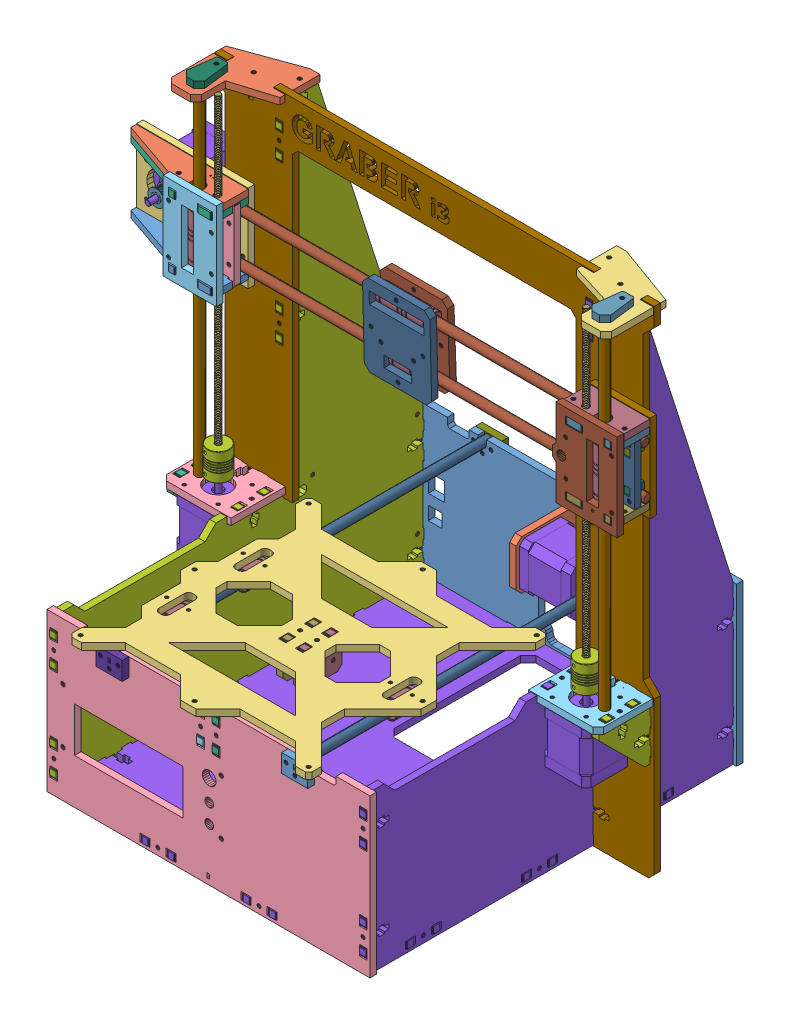
SolidWorks assembly Assem1, configuration Default. Lengths in mm.
Overall size (470.04 461.9 366.24).
68 component instances, 50 part files, 200 mates.
Components (placement in the parent):
- back part 1-1: back part 1 [Default] at (81.0271 401.4745 20.7029) x (-1 0 0) z (0 0 -1) size (296 144.5 6)
- back part 2-1: back part 2 [Default] at (199.6219 473.5631 193.2658) x (0 0 1) z (-1 0 0) size (71.85 45 6)
- bed-1: bed [Default] at (-163.14 330.8347 15.6908) x (1 0 0) z (0 -1 0) size (220.33 220.31 6)
- front part 1 screen-1: front part 1 screen [Default] at (294.9167 578.5677 350.6028) size (296 144.5 6)
- front part 2a-1: front part 2a [Default] at (183.3219 631.05 272.14) x (0 0 1) z (-1 0 0) size (40.75 45 6)
- front part 2b-1: front part 2b [Default] at (197.7219 678.4694 271.6813) x (0 0 1) z (-1 0 0) size (40.75 45 6)
- leg left-1: leg left [Default] at (48.822 231.9538 579.6805) x (0 0 1) z (-1 0 0) size (342.6 449.9 6)
- leg right-1: leg right [Default] at (326.8719 230.1655 151.8741) x (0 0 -1) z (1 0 0) size (342.6 449.9 6)
- main frame-1: main frame [Default] at (-176.0058 230.1655 143.6028) size (402.95 456 6)
- n1-1: n1 [Default] at (218.3242 369.7719 164.9112) x (1 0 0) z (0 -0.024034 0.999711) size (61.69 75.91 6)
- n2-1: n2 [Default] at (218.3242 294.4964 143.8985) x (1 0 0) z (0 -0.036374 0.999338) size (61.69 75.91 6)
- part p-1: part p [Default] at (183.563 14.2222 -89.1173) x (0 0 1) z (-1 0 0) size (38.6 31.35 6)
- part p b-1: part p b [Default] at (193.0605 14.3436 15.5535) x (0 1 0) z (1 0 0) size (31.35 38.6 6)
- small top a-1: small top a [Default] at (-87.2919 634.6064 375.2986) x (1 0 0) z (0 1 0) size (16.77 30.05 6)
- small top b-1: small top b [Default] at (-472.4014 634.6064 421.3951) x (1 0 0) z (0 1 0) size (16.77 30.05 6)
- smooth rod stop a-1: smooth rod stop a [Default] at (-150.0515 246.7717 8.7029) size (24 16.7 6)
- smooth rod stop b-1: smooth rod stop b [Default] at (-149.8049 227.3403 356.6028) size (24 16.7 6)
- smooth rod stop c-1: smooth rod stop c [Default] at (20.1883 207.2244 8.7029) size (24 16.7 6)
- smooth rod stop d-1: smooth rod stop d [Default] at (20.273 187.8996 356.6028) size (24 16.7 6)
- smooth rod top a-1: smooth rod top a [Default] at (-31.7202 634.6064 605.6389) x (0 0 -1) z (0 -1 0) size (75.26 65.68 6)
- smooth rod top b-1: smooth rod top b [Default] at (726.9539 628.6064 93.7708) x (-1 0 0) z (0 1 0) size (65.68 75.26 6)
- stepper base left-1: stepper base left [Default] at (-280.2567 316.9564 234.6953) x (1 0 0) z (0 1 0) size (64 56.35 6)
- stepper base right-1: stepper base right [Default] at (56.5293 316.9065 293.4958) x (1 0 0) z (0 1 0) size (64 56.35 6)
- stepper stand a-1: stepper stand a [Default] at (-9.948 -106.3457 57.6908) x (0 1 0) z (1 0 0) size (53.35 53.34 6)
- stepper stand b-1: stepper stand b [Default] at (385.6419 172.2943 -219.6051) x (0 0 1) z (-1 0 0) size (53.35 53.34 6)
- under bed-1: under bed [Default] at (-55.3058 181.7065 435.9358) x (0 0 1) z (0 1 0) size (342.6 289.5 6)
- x idler part 1-1: x idler part 1 [Default] at (847.1674 642.4594 153.83) size (59 79.9 6)
- x idler part 2-1: x idler part 2 [Default] at (787.0156 643.2594 167.8319) size (59 65.1 6)
- x idler part 3-1: x idler part 3 [Default] at (727.0679 642.4594 184.03) size (59 79.9 6)
- x idler part 4-1: x idler part 4 [Default] at (484.4835 487.9462 483.2321) x (0 0 1) z (0 1 0) size (36.8 55 6)
- x idler part 5-1: x idler part 5 [Default] at (847.3015 547.8462 -9.8219) x (1 0 0) z (0 1 0) size (55 23.6 6)
- x idler part 6-1: x idler part 6 [Default] at (790.9011 547.8462 -9.4918) x (1 0 0) z (0 1 0) size (55 36.8 6)
- x idler part 7a-1: x idler part 7a [Default] at (755.5095 496.5462 -13.5225) x (1 0 0) z (0 1 0) size (29.97 17.5 6)
- x idler part 7b-1: x idler part 7b [Default] at (724.0344 527.1462 -13.5044) x (1 0 0) z (0 1 0) size (29.97 17.5 6)
- x motor part 1-1: x motor part 1 [Default] at (491.673 525.4551 -71.4672) x (1 0 0) z (0 1 0) size (29.97 17.5 6)
- x motor part 1b-1: x motor part 1b [Default] at (449.1595 495.6551 -77.763) x (1 0 0) z (0 1 0) size (29.97 17.5 6)
- x motor part 2-1: x motor part 2 [Default] at (-481.484 487.0551 437.8787) x (-1 0 0) z (0 1 0) size (102.7 36.8 6)
- x motor part 3-1: x motor part 3 [Default] at (-377.0341 546.9551 445.1095) x (-1 0 0) z (0 1 0) size (102.7 23.6 6)
- x motor part 4-1: x motor part 4 [Default] at (434.2486 839.5242 154.4392) size (102.3 79.9 6)
- x motor part 5-1: x motor part 5 [Default] at (384.0037 188.4825 174.4392) x (1 0 0) z (0 0 -1) size (48.7 65.1 6)
- x motor part 6-1: x motor part 6 [Default] at (332.3799 840.721 184.0392) size (48.7 79.9 6)
- x motor part 7-1: x motor part 7 [Default] at (434.9095 546.9551 -213.9017) x (1 0 0) z (0 1 0) size (102.7 36.8 6)
- Flexi_spojka_5x5-1: Flexi_spojka_5x5 [Default] at (19.3155 338.4564 178.8274) x (0 1 0) z (0 0 1) size (25 21.03 20)
- nema17-1: nema17 [Défaut] at (356.4592 316.9065 178.8223) x (1 0 0.000118) z (0 -1 0) size (42 42 71)
- smooth rod 8x317-1: smooth rod 8x317 [Default] at (2.2936 316.9564 178.9402) size (8 317 8)
- smooth rod 8x342-1: smooth rod 8x342 [Default] at (272.9623 319.2422 14.6028) x (-0.956375 -0.292142 0) z (-0.292142 0.956375 0) size (8 342 8)
- smooth rod 8x400-1: smooth rod 8x400 [Default] at (-4.2443 491.9462 162.4699) x (0 -1 0) z (0 0 1) size (8 400 8)
- smooth rod 8x342-2: smooth rod 8x342 [Default] at (102.9608 319.2481 14.6028) x (-0.222657 0.974897 0) z (0.974897 0.222657 0) size (8 342 8)
- nema17-2: nema17 [Défaut] at (19.3155 316.9564 178.8274) x (1 0 0) z (0 -1 0) size (42 42 71)
- threaded rod 5mm-1: threaded rod 5mm [Défaut] at (356.4592 632.9065 178.8223) x (0 -1 0) z (0 0 1) size (293.85 5.77 5.1)
- threaded rod 5mm-2: threaded rod 5mm [Défaut] at (19.3155 632.9564 178.8274) x (0 -1 0) z (-0.747424 0 0.664347) size (293.85 5.77 5.1)
- Flexi_spojka_5x5-2: Flexi_spojka_5x5 [Default] at (356.4592 338.4065 178.8223) x (0 1 0) z (0.084195 0 0.996449) size (25 21.03 20)
- smooth rod 8x317-2: smooth rod 8x317 [Default] at (373.3732 316.9065 178.9309) size (8 317 8)
- LM8UU-1: LM8UU [Default] at (102.9608 319.2481 230.7856) x (0 0 -1) z (0.945065 -0.326884 0) size (24 15 15)
- LM8UU-2: LM8UU [Default] at (102.9608 319.2481 300.7926) x (0 0 1) z (-0.81584 -0.578277 0) size (24 15 15)
- LM8UU-3: LM8UU [Default] at (272.9623 319.2422 264.6485) x (0 0 1) z (-0.995879 -0.090696 0) size (24 15 15)
- LM8UU-4: LM8UU [Default] at (2.2936 527.4051 178.9402) x (0 1 0) z (-0.980384 0 0.197099) size (24 15 15)
- smooth rod 8x400-2: smooth rod 8x400 [Default] at (-4.2443 536.9551 163.83) x (0 -1 0) z (0 0 1) size (8 400 8)
- LM8UU-5: LM8UU [Default] at (2.2936 503.4051 178.9402) x (0 1 0) z (-0.980384 0 0.197099) size (24 15 15)
- LM8UU-6: LM8UU [Default] at (191.6084 536.9551 163.83) x (1 0 0) z (0 0.980384 0.197099) size (24 15 15)
- LM8UU-7: LM8UU [Default] at (178.1084 491.9462 162.4699) x (-1 0 0) z (0 -0.980384 0.197099) size (24 15 15)
- LM8UU-8: LM8UU [Default] at (167.6084 536.9551 163.83) x (-1 0 0) z (0 -0.980384 0.197099) size (24 15 15)
- LM8UU-9: LM8UU [Default] at (373.3732 503.4962 178.9309) x (0 -1 0) z (-0.81584 0 -0.578277) size (24 15 15)
- LM8UU-10: LM8UU [Default] at (373.3732 527.4962 178.9309) x (0 1 0) z (-0.81584 0 0.578277) size (24 15 15)
- nema17-3: nema17 [Défaut] at (-46.089 513.5551 154.4392) x (1 0 0) z (0 0 -1) size (42 42 71)
- nema17-4: nema17 [Défaut] at (199.6219 299.8274 62.2029) x (0 -1 0) z (1 0 0) size (42 42 71)
- GT2_20tooth-1: GT2_20tooth [Конфигурация1] at (197.8286 299.8274 62.2029) x (-1 0 0) z (0 -0.924225 -0.381849) size (14 15 15)
- GT2_20tooth-2: GT2_20tooth [Конфигурация1] at (-46.089 513.5551 156.4392) x (0 0 1) z (-1 0 0) size (14 15 15)
Mates (geometry in assembly coordinates):
- Distance1: distance = 0.35 mm anti-aligned: plane of leg left-1 through (42.822 231.9538 579.6805) normal (-1 0 0); plane of main frame-1 through (42.472 230.1655 149.6028) normal (1 0 0)
- Coincident2: coincident anti-aligned: plane of leg left-1 through (42.822 231.9538 143.6028) normal (0 0 1); plane of main frame-1 through (-176.0058 230.1655 143.6028) normal (0 0 -1)
- Coincident4: coincident aligned: plane of leg left-1 through (42.822 178.7065 579.6805) normal (0 -1 0); plane of main frame-1 through (-176.0058 178.7065 149.6028) normal (0 -1 0)
- Coincident5: coincident anti-aligned: plane of leg right-1 through (332.8719 230.1655 143.6028) normal (0 0 1); plane of main frame-1 through (-176.0058 230.1655 143.6028) normal (0 0 -1)
- Coincident6: coincident aligned: plane of leg left-1 through (42.822 178.7065 579.6805) normal (0 -1 0); plane of leg right-1 through (332.8719 178.7065 151.8741) normal (0 -1 0)
- Distance2: distance = 0.35 mm anti-aligned: plane of leg right-1 through (332.8719 230.1655 151.8741) normal (1 0 0); plane of main frame-1 through (333.2219 230.1655 149.6028) normal (-1 0 0)
- Coincident8: coincident anti-aligned: plane of front part 1 screen-1 through (294.9167 578.5677 350.6028) normal (0 0 -1); plane of leg left-1 through (42.822 231.9538 350.6028) normal (0 0 1)
- Coincident9: coincident aligned: plane of front part 1 screen-1 through (294.9167 178.7065 356.6028) normal (0 -1 0); plane of leg left-1 through (42.822 178.7065 579.6805) normal (0 -1 0)
- Coincident11: coincident anti-aligned: plane of front part 1 screen-1 through (42.822 578.5677 356.6028) normal (1 0 0); plane of leg left-1 through (42.822 231.9538 579.6805) normal (-1 0 0)
- Coincident12: coincident anti-aligned: plane of back part 1-1 through (81.0271 401.4745 20.7029) normal (0 0 1); plane of leg right-1 through (332.8719 230.1655 20.7029) normal (0 0 -1)
- Coincident13: coincident aligned: plane of back part 1-1 through (81.0271 178.7065 14.7029) normal (0 -1 0); plane of leg right-1 through (332.8719 178.7065 151.8741) normal (0 -1 0)
- Coincident15: coincident aligned: plane of back part 1-1 through (335.9719 401.4745 14.7029) normal (1 0 0); plane of front part 1 screen-1 through (335.9719 578.5677 356.6028) normal (1 0 0)
- Parallel2: parallel anti-aligned: plane of leg right-1 through (332.8719 178.7065 151.8741) normal (0 -1 0); plane of under bed-1 through (-55.3058 187.7065 435.9358) normal (0 1 0)
- Coincident17: coincident anti-aligned: plane of back part 1-1 through (81.0271 401.4745 20.7029) normal (0 0 1); plane of under bed-1 through (-55.3058 187.7065 20.7029) normal (0 0 -1)
- Coincident18: coincident anti-aligned: plane of leg left-1 through (42.822 181.7065 579.6805) normal (0 1 0); plane of under bed-1 through (-55.3058 181.7065 435.9358) normal (0 -1 0)
- Coincident19: coincident anti-aligned: plane of leg right-1 through (326.8719 230.1655 151.8741) normal (-1 0 0); plane of under bed-1 through (326.8719 187.7065 435.9358) normal (1 0 0)
- Coincident20: coincident anti-aligned: plane of main frame-1 through (-176.0058 230.1655 149.6028) normal (0 0 1); plane of stepper base left-1 through (-280.2567 322.9564 149.6028) normal (0 0 -1)
- Coincident22: coincident anti-aligned: plane of main frame-1 through (-176.0058 316.9564 149.6028) normal (0 1 0); plane of stepper base left-1 through (-280.2567 316.9564 234.6953) normal (0 -1 0)
- Coincident23: coincident anti-aligned: plane of stepper base left-1 through (-280.2567 316.9564 234.6953) normal (0 -1 0); plane of stepper stand a-1 through (-3.948 316.9564 57.6908) normal (0 1 0)
- Coincident24: coincident anti-aligned: plane of main frame-1 through (-176.0058 230.1655 149.6028) normal (0 0 1); plane of stepper stand a-1 through (-3.948 -106.3457 149.6028) normal (0 0 -1)
- Coincident25: coincident anti-aligned: plane of stepper base left-1 through (-3.948 322.9564 234.6953) normal (-1 0 0); plane of stepper stand a-1 through (-3.948 -106.3457 57.6908) normal (1 0 0)
- Distance4: distance = 0.33 mm anti-aligned: plane of leg left-1 through (42.822 231.9538 579.6805) normal (-1 0 0); plane of stepper base left-1 through (42.492 322.9564 234.6953) normal (1 0 0)
- Coincident27: coincident anti-aligned: plane of main frame-1 through (-176.0058 230.1655 149.6028) normal (0 0 1); plane of stepper base right-1 through (56.5293 322.9065 149.6028) normal (0 0 -1)
- Coincident28: coincident anti-aligned: plane of leg right-1 through (332.8719 316.9065 151.8741) normal (0 1 0); plane of stepper base right-1 through (56.5293 316.9065 293.4958) normal (0 -1 0)
- Distance5: distance = 0.33 mm anti-aligned: plane of leg right-1 through (332.8719 230.1655 151.8741) normal (1 0 0); plane of stepper base right-1 through (333.2019 322.9065 293.4958) normal (-1 0 0)
- Coincident30: coincident anti-aligned: plane of stepper base right-1 through (56.5293 316.9065 293.4958) normal (0 -1 0); plane of stepper stand b-1 through (379.6419 316.9065 -219.6051) normal (0 1 0)
- Coincident31: coincident anti-aligned: plane of main frame-1 through (-176.0058 230.1655 149.6028) normal (0 0 1); plane of stepper stand b-1 through (379.6419 172.2943 149.6028) normal (0 0 -1)
- Coincident32: coincident anti-aligned: plane of stepper base right-1 through (379.6419 322.9065 293.4958) normal (1 0 0); plane of stepper stand b-1 through (379.6419 172.2943 -219.6051) normal (-1 0 0)
- Tangent1: tangent anti-aligned: plane of front part 1 screen-1 through (260.4614 316.8535 356.6028) normal (0.130526 0.991445 0); cylinder of smooth rod 8x342-1 through (272.9623 319.2422 356.6028) axis (0 0 -1) radius 4
- Tangent2: tangent anti-aligned: plane of front part 1 screen-1 through (414.4603 422.7756 356.6028) normal (-0.608761 0.793353 0); cylinder of smooth rod 8x342-1 through (272.9623 319.2422 356.6028) axis (0 0 -1) radius 4
- Tangent3: tangent anti-aligned: plane of front part 1 screen-1 through (173.5914 285.6624 356.6028) normal (0.382683 0.92388 0); cylinder of smooth rod 8x342-2 through (102.9608 319.2481 356.6028) axis (0 0 -1) radius 4
- Tangent4: tangent anti-aligned: plane of front part 1 screen-1 through (302.513 572.7389 356.6028) normal (-0.793353 0.608761 0); cylinder of smooth rod 8x342-2 through (102.9608 319.2481 356.6028) axis (0 0 -1) radius 4
- Coincident34: coincident anti-aligned: plane of back part 1-1 through (81.0271 401.4745 14.7029) normal (0 0 -1); plane of smooth rod stop a-1 through (-150.0515 246.7717 14.7029) normal (0 0 1)
- Coincident35: coincident anti-aligned: plane of front part 1 screen-1 through (294.9167 578.5677 356.6028) normal (0 0 1); plane of smooth rod stop d-1 through (20.273 187.8996 356.6028) normal (0 0 -1)
- Coincident36: coincident anti-aligned: plane of front part 1 screen-1 through (294.9167 578.5677 356.6028) normal (0 0 1); plane of smooth rod stop b-1 through (-149.8049 227.3403 356.6028) normal (0 0 -1)
- Coincident37: coincident anti-aligned: plane of back part 1-1 through (81.0271 401.4745 14.7029) normal (0 0 -1); plane of smooth rod stop c-1 through (20.1883 207.2244 14.7029) normal (0 0 1)
- Coincident38: coincident anti-aligned: plane of smooth rod stop b-1 through (-149.8049 227.3403 356.6028) normal (0 0 -1); plane of smooth rod 8x342-2 through (102.9608 319.2481 356.6028) normal (0 0 1)
- Coincident39: coincident aligned: plane of front part 1 screen-1 through (294.9167 323.2065 356.6028) normal (0 1 0); plane of smooth rod stop b-1 through (-149.8049 323.2065 362.6028) normal (0 1 0)
- Coincident40: coincident anti-aligned: plane of smooth rod stop d-1 through (20.273 187.8996 356.6028) normal (0 0 -1); plane of smooth rod 8x342-1 through (272.9623 319.2422 356.6028) normal (0 0 1)
- Coincident41: coincident aligned: plane of front part 1 screen-1 through (294.9167 323.2065 356.6028) normal (0 1 0); plane of smooth rod stop d-1 through (20.273 323.2065 362.6028) normal (0 1 0)
- Coincident42: coincident aligned: plane of back part 1-1 through (81.0271 323.2065 14.7029) normal (0 1 0); plane of smooth rod stop a-1 through (-150.0515 323.2065 14.7029) normal (0 1 0)
- Coincident43: coincident aligned: plane of back part 1-1 through (81.0271 323.2065 14.7029) normal (0 1 0); plane of smooth rod stop c-1 through (20.1883 323.2065 14.7029) normal (0 1 0)
- Coincident44: coincident aligned: plane of front part 1 screen-1 through (257.4547 294.0152 356.6028) normal (0.130526 0.991445 0); plane of smooth rod stop b-1 through (-134.2381 345.5825 362.6028) normal (0.130526 0.991445 0)
- Coincident45: coincident aligned: plane of front part 1 screen-1 through (260.6236 318.0852 356.6028) normal (0.130526 0.991445 0); plane of smooth rod stop d-1 through (41.2152 346.9709 362.6028) normal (0.130526 0.991445 0)
- Coincident46: coincident aligned: plane of back part 1-1 through (96.2765 285.6441 14.7029) normal (-0.130526 0.991445 0); plane of smooth rod stop c-1 through (11.3363 274.4615 14.7029) normal (-0.130526 0.991445 0)
- Coincident47: coincident aligned: plane of back part 1-1 through (93.3802 307.6437 14.7029) normal (-0.130526 0.991445 0); plane of smooth rod stop a-1 through (-153.7816 275.1042 14.7029) normal (-0.130526 0.991445 0)
- Coincident48: coincident anti-aligned: plane of stepper base right-1 through (56.5293 316.9065 293.4958) normal (0 -1 0); plane of nema17-1 through (356.4592 316.9065 178.8223) normal (0 1 0)
- Tangent5: tangent anti-aligned: plane of stepper base right-1 through (138.3592 322.9065 95.941) normal (-0.382683 0 0.92388); cylinder of nema17-1 through (371.9574 311.9065 194.3241) axis (0 1 0) radius 1.5
- Tangent6: tangent anti-aligned: plane of stepper base right-1 through (74.4052 322.9065 157.7152) normal (-0.130526 0 0.991445); cylinder of nema17-1 through (340.9574 311.9065 194.3204) axis (0 1 0) radius 1.5
- Tangent7: tangent anti-aligned: plane of stepper base right-1 through (237.2066 322.9065 58.0326) normal (-0.608761 0 0.793353); cylinder of nema17-1 through (371.9611 311.9065 163.3241) axis (0 1 0) radius 1.5
- Coincident49: coincident anti-aligned: plane of stepper base left-1 through (-280.2567 316.9564 234.6953) normal (0 -1 0); plane of nema17-2 through (19.3155 316.9564 178.8274) normal (0 1 0)
- Tangent8: tangent anti-aligned: plane of stepper base left-1 through (-219.2692 322.9564 87.4585) normal (-0.382683 0 0.92388); cylinder of nema17-2 through (34.8155 311.9564 194.3274) axis (0 1 0) radius 1.5
- Tangent9: tangent anti-aligned: plane of stepper base left-1 through (-154.5729 322.9564 70.901) normal (-0.608761 0 0.793353); cylinder of nema17-2 through (3.8155 311.9564 194.3274) axis (0 1 0) radius 1.5
- Tangent10: tangent anti-aligned: plane of stepper base left-1 through (-212.8489 322.9564 71.9585) normal (-0.382683 0 0.92388); cylinder of nema17-2 through (3.8155 311.9564 163.3274) axis (0 1 0) radius 1.5
- Concentric1: concentric anti-aligned: cylinder of nema17-1 through (356.4592 340.9065 178.8223) axis (0 -1 0) radius 2.5; cylinder of threaded rod 5mm-1 through (356.4592 340.9065 178.8223) axis (0 1 0) radius 2.5
- Coincident50: coincident anti-aligned: plane of nema17-1 through (356.4592 340.9065 178.8223) normal (0 1 0); plane of threaded rod 5mm-1 through (356.4592 340.9065 178.8223) normal (0 -1 0)
- Concentric2: concentric anti-aligned: cylinder of nema17-2 through (19.3155 340.9564 178.8274) axis (0 -1 0) radius 2.5; cylinder of threaded rod 5mm-2 through (19.3155 340.9564 178.8274) axis (0 1 0) radius 2.5
- Coincident51: coincident anti-aligned: plane of nema17-2 through (19.3155 340.9564 178.8274) normal (0 1 0); plane of threaded rod 5mm-2 through (19.3155 340.9564 178.8274) normal (0 -1 0)
- Concentric3: concentric anti-aligned: cylinder of nema17-1 through (356.4592 340.9065 178.8223) axis (0 -1 0) radius 2.5; cylinder of Flexi_spojka_5x5-2 through (356.4592 330.9065 178.8223) axis (0 1 0) radius 2.5
- Concentric4: concentric anti-aligned: cylinder of Flexi_spojka_5x5-1 through (19.3155 330.9564 178.8274) axis (0 1 0) radius 2.5; cylinder of nema17-2 through (19.3155 340.9564 178.8274) axis (0 -1 0) radius 2.5
- Distance6: distance = 12 mm anti-aligned: plane of Flexi_spojka_5x5-1 through (19.3155 330.9564 178.8274) normal (0 -1 0); plane of nema17-2 through (19.3155 318.9564 178.8274) normal (0 1 0)
- Distance7: distance = 12 mm anti-aligned: plane of Flexi_spojka_5x5-2 through (356.4592 330.9065 178.8223) normal (0 -1 0); plane of nema17-1 through (356.4592 318.9065 178.8223) normal (0 1 0)
- Coincident54: coincident anti-aligned: plane of main frame-1 through (-176.0058 628.6064 149.6028) normal (0 1 0); plane of smooth rod top a-1 through (-31.7202 628.6064 605.6389) normal (0 -1 0)
- Coincident55: coincident anti-aligned: plane of main frame-1 through (-176.0058 230.1655 143.6028) normal (0 0 -1); plane of smooth rod top a-1 through (-31.7202 628.6064 143.6028) normal (0 0 1)
- Coincident57: coincident anti-aligned: plane of main frame-1 through (-176.0058 628.6064 149.6028) normal (0 1 0); plane of smooth rod top b-1 through (726.9539 628.6064 93.7708) normal (0 -1 0)
- Coincident58: coincident anti-aligned: plane of main frame-1 through (-176.0058 230.1655 143.6028) normal (0 0 -1); plane of smooth rod top b-1 through (726.9539 634.6064 143.6028) normal (0 0 1)
- Tangent11: tangent anti-aligned: plane of stepper base right-1 through (77.2753 322.9065 135.9144) normal (-0.130526 0 0.991445); cylinder of smooth rod 8x317-2 through (373.3732 633.9065 178.9309) axis (0 -1 0) radius 4
- Tangent12: tangent anti-aligned: plane of stepper base right-1 through (290.1632 322.9065 390.2701) normal (-0.92388 0 -0.382683); cylinder of smooth rod 8x317-2 through (373.3732 633.9065 178.9309) axis (0 -1 0) radius 4
- Coincident60: coincident aligned: plane of stepper base right-1 through (56.5293 316.9065 293.4958) normal (0 -1 0); plane of smooth rod 8x317-2 through (373.3732 316.9065 178.9309) normal (0 -1 0)
- Coincident61: coincident anti-aligned: plane of main frame-1 through (334.7219 230.1655 149.6028) normal (1 0 0); plane of smooth rod top b-1 through (334.7219 634.6064 93.7708) normal (-1 0 0)
- Tangent14: tangent anti-aligned: plane of stepper base left-1 through (-267.7055 322.9564 139.3596) normal (-0.130526 0 0.991445); cylinder of smooth rod 8x317-1 through (2.2936 633.9564 178.9402) axis (0 -1 0) radius 4
- Tangent15: tangent anti-aligned: plane of stepper base left-1 through (-62.4929 322.9564 324.896) normal (0.92388 0 0.382683); cylinder of smooth rod 8x317-1 through (2.2936 633.9564 178.9402) axis (0 -1 0) radius 4
- Coincident62: coincident aligned: plane of stepper base left-1 through (-280.2567 316.9564 234.6953) normal (0 -1 0); plane of smooth rod 8x317-1 through (2.2936 316.9564 178.9402) normal (0 -1 0)
- Coincident63: coincident anti-aligned: plane of main frame-1 through (40.972 230.1655 149.6028) normal (-1 0 0); plane of smooth rod top a-1 through (40.972 628.6064 605.6389) normal (1 0 0)
- Concentric5: concentric anti-aligned: cylinder of smooth rod 8x342-2 through (102.9608 319.2481 356.6028) axis (0 0 -1) radius 4; cylinder of LM8UU-1 through (102.9608 319.2481 276.4751) axis (0 0 1) radius 4
- Concentric61: concentric aligned: cylinder of smooth rod 8x342-2 through (102.9608 319.2481 356.6028) axis (0 0 -1) radius 4; cylinder of LM8UU-2 through (102.9608 319.2481 255.1031) axis (0 0 -1) radius 7.5
- Concentric71: concentric aligned: cylinder of smooth rod 8x342-1 through (272.9623 319.2422 356.6028) axis (0 0 -1) radius 4; cylinder of LM8UU-3 through (272.9623 319.2422 218.959) axis (0 0 -1) radius 7.5
- Coincident64: coincident anti-aligned: plane of back part 1-1 through (81.0271 401.4745 20.7029) normal (0 0 1); plane of back part 2-1 through (193.6219 473.5631 20.7029) normal (0 0 -1)
- Coincident65: coincident anti-aligned: plane of back part 1-1 through (193.6219 401.4745 14.7029) normal (1 0 0); plane of back part 2-1 through (193.6219 473.5631 193.2658) normal (-1 0 0)
- Coincident66: coincident anti-aligned: plane of back part 1-1 through (81.0271 307.4274 14.7029) normal (0 1 0); plane of back part 2-1 through (193.6219 307.4274 193.2658) normal (0 -1 0)
- Coincident67: coincident aligned: plane of front part 2a-1 through (177.3219 631.05 350.6028) normal (0 0 1); plane of front part 2b-1 through (191.7219 678.4694 350.6028) normal (0 0 1)
- Coincident68: coincident anti-aligned: plane of front part 1 screen-1 through (294.9167 578.5677 350.6028) normal (0 0 -1); plane of front part 2b-1 through (191.7219 678.4694 350.6028) normal (0 0 1)
- Coincident69: coincident anti-aligned: plane of front part 1 screen-1 through (294.9167 317.2465 356.6028) normal (0 -1 0); plane of front part 2a-1 through (177.3219 317.2465 272.14) normal (0 1 0)
- Coincident71: coincident anti-aligned: plane of front part 1 screen-1 through (191.7219 578.5677 356.6028) normal (1 0 0); plane of front part 2b-1 through (191.7219 678.4694 271.6813) normal (-1 0 0)
- Coincident72: coincident anti-aligned: plane of front part 1 screen-1 through (177.3219 578.5677 356.6028) normal (1 0 0); plane of front part 2a-1 through (177.3219 631.05 272.14) normal (-1 0 0)
- Coincident73: coincident anti-aligned: plane of front part 1 screen-1 through (294.9167 308.0465 356.6028) normal (0 1 0); plane of front part 2b-1 through (191.7219 308.0465 271.6813) normal (0 -1 0)
- Coincident74: coincident anti-aligned: plane of small top b-1 through (-472.4014 634.6064 421.3951) normal (0 -1 0); plane of smooth rod top a-1 through (-31.7202 634.6064 605.6389) normal (0 1 0)
- Coincident75: coincident anti-aligned: plane of small top a-1 through (-87.2919 634.6064 375.2986) normal (0 -1 0); plane of smooth rod top b-1 through (726.9539 634.6064 93.7708) normal (0 1 0)
- Coincident76: coincident aligned: plane of small top a-1 through (-52.2335 640.6064 109.0039) normal (0.130526 0 -0.991445); plane of smooth rod top b-1 through (711.7076 634.6064 209.5786) normal (0.130526 0 -0.991445)
- Coincident77: coincident aligned: plane of small top a-1 through (-17.731 640.6064 465.9521) normal (-0.608761 0 -0.793353); plane of smooth rod top b-1 through (630.7306 634.6064 -31.63) normal (-0.608761 0 -0.793353)
- Coincident78: coincident aligned: plane of small top b-1 through (25.4669 640.6064 355.8495) normal (0.991445 0 -0.130526); plane of smooth rod top a-1 through (56.8178 628.6064 593.9827) normal (0.991445 0 -0.130526)
- Coincident79: coincident aligned: plane of small top b-1 through (-312.3674 640.6064 35.039) normal (0.382683 0 -0.92388); plane of smooth rod top a-1 through (128.9175 628.6064 217.8252) normal (0.382683 0 -0.92388)
- Parallel3: parallel anti-aligned: plane of bed-1 through (-163.14 324.8347 15.6908) normal (0 -1 0); plane of leg left-1 through (42.822 313.2065 579.6805) normal (0 1 0)
- Coincident80: coincident: line of bed-1 through (107.9649 324.8347 241.7856) axis (0 0 -1); cylinder of LM8UU-1 through (102.9608 319.2481 276.4751) axis (0 0 1) radius 7.5
- Coincident81: coincident: line of bed-1 through (107.9649 324.8347 311.7926) axis (0 0 -1); cylinder of LM8UU-2 through (102.9608 319.2481 255.1031) axis (0 0 -1) radius 7.5
- Coincident82: coincident: line of bed-1 through (267.9648 324.8347 252.6485) axis (0 0 1); cylinder of LM8UU-3 through (272.9623 319.2422 218.959) axis (0 0 -1) radius 7.5
- Distance8: distance = 4 mm anti-aligned: plane of bed-1 through (-163.14 324.8347 284.7926) normal (0 0 1); plane of LM8UU-2 through (102.9608 319.2481 288.7926) normal (0 0 -1)
- Distance9: distance = 4 mm anti-aligned: plane of LM8UU-1 through (102.9608 319.2481 218.7856) normal (0 0 -1); plane of bed-1 through (-163.14 324.8347 214.7856) normal (0 0 1)
- Distance10: distance = 4 mm anti-aligned: plane of LM8UU-3 through (272.9623 319.2422 252.6485) normal (0 0 -1); plane of bed-1 through (-163.14 324.8347 248.6485) normal (0 0 1)
- Coincident86: coincident anti-aligned: plane of x motor part 3-1 through (-377.0341 552.9551 160.4392) normal (0 0 -1); plane of x motor part 4-1 through (434.2486 839.5242 160.4392) normal (0 0 1)
- Coincident87: coincident anti-aligned: plane of x motor part 2-1 through (-481.484 481.0551 160.4392) normal (0 0 -1); plane of x motor part 4-1 through (434.2486 839.5242 160.4392) normal (0 0 1)
- Coincident88: coincident anti-aligned: plane of x motor part 4-1 through (434.2486 839.5242 160.4392) normal (0 0 1); plane of x motor part 7-1 through (434.9095 540.9551 160.4392) normal (0 0 -1)
- Parallel4: parallel aligned: plane of x motor part 4-1 through (-74.089 839.5242 160.4392) normal (-1 0 0); plane of x motor part 7-1 through (-74.289 540.9551 -213.9017) normal (-1 0 0)
- Parallel5: parallel aligned: plane of x motor part 3-1 through (-74.289 552.9551 445.1095) normal (-1 0 0); plane of x motor part 4-1 through (-74.089 839.5242 160.4392) normal (-1 0 0)
- Parallel6: parallel aligned: plane of x motor part 2-1 through (-74.289 481.0551 437.8787) normal (-1 0 0); plane of x motor part 4-1 through (-74.089 839.5242 160.4392) normal (-1 0 0)
- Coincident89: coincident anti-aligned: plane of x motor part 2-1 through (23.211 481.0551 437.8787) normal (1 0 0); plane of x motor part 4-1 through (23.211 839.5242 160.4392) normal (-1 0 0)
- Coincident90: coincident anti-aligned: plane of x motor part 4-1 through (23.211 839.5242 160.4392) normal (-1 0 0); plane of x motor part 7-1 through (23.211 540.9551 -213.9017) normal (1 0 0)
- Coincident91: coincident anti-aligned: plane of x motor part 2-1 through (-481.484 487.0551 437.8787) normal (0 1 0); plane of x motor part 4-1 through (434.2486 487.0551 160.4392) normal (0 -1 0)
- Coincident92: coincident anti-aligned: plane of x motor part 4-1 through (434.2486 546.9551 160.4392) normal (0 -1 0); plane of x motor part 7-1 through (434.9095 546.9551 -213.9017) normal (0 1 0)
- Coincident93: coincident anti-aligned: plane of x motor part 3-1 through (-377.0341 546.9551 445.1095) normal (0 -1 0); plane of x motor part 7-1 through (434.9095 546.9551 -213.9017) normal (0 1 0)
- Coincident94: coincident aligned: plane of x motor part 3-1 through (28.4093 552.9551 445.1095) normal (1 0 0); plane of x motor part 7-1 through (28.4093 540.9551 -213.9017) normal (1 0 0)
- Coincident95: coincident anti-aligned: plane of x motor part 6-1 through (332.3799 840.721 184.0392) normal (0 0 -1); plane of x motor part 7-1 through (434.9095 540.9551 184.0392) normal (0 0 1)
- Coincident96: coincident anti-aligned: plane of x motor part 6-1 through (332.3799 540.9551 190.0392) normal (0 1 0); plane of x motor part 7-1 through (434.9095 540.9551 -213.9017) normal (0 -1 0)
- Coincident97: coincident anti-aligned: plane of x motor part 2-1 through (11.5987 481.0551 437.8787) normal (-1 0 0); plane of x motor part 6-1 through (11.5987 840.721 190.0392) normal (1 0 0)
- Tangent19: tangent: line of x motor part 6-1 through (7.7935 489.4051 184.0392) axis (0 1 0); cylinder of LM8UU-4 through (2.2936 481.7156 178.9402) axis (0 -1 0) radius 7.5
- Tangent17: tangent: line of x motor part 6-1 through (-3.2064 539.4051 184.0392) axis (0 -1 0); cylinder of LM8UU-4 through (2.2936 481.7156 178.9402) axis (0 -1 0) radius 7.5
- Concentric8: concentric aligned: cylinder of LM8UU-4 through (2.2936 481.7156 178.9402) axis (0 -1 0) radius 7.5; cylinder of LM8UU-5 through (2.2936 457.7156 178.9402) axis (0 -1 0) radius 7.5
- Coincident101: coincident anti-aligned: plane of LM8UU-4 through (2.2936 515.4051 178.9402) normal (0 -1 0); plane of LM8UU-5 through (2.2936 515.4051 178.9402) normal (0 1 0)
- Coincident102: coincident anti-aligned: plane of x motor part 6-1 through (332.3799 539.4051 190.0392) normal (0 -1 0); plane of LM8UU-4 through (2.2936 539.4051 178.9402) normal (0 1 0)
- Parallel7: parallel anti-aligned: plane of x motor part 4-1 through (434.2486 839.5242 160.4392) normal (0 0 1); plane of x motor part 5-1 through (384.0037 188.4825 168.4392) normal (0 0 -1)
- Tangent20: tangent: line of x motor part 5-1 through (8.2928 526.2551 174.4392) axis (0 -1 0); cylinder of LM8UU-5 through (2.2936 457.7156 178.9402) axis (0 -1 0) radius 7.5
- Coincident106: coincident anti-aligned: plane of x motor part 2-1 through (-481.484 481.0551 168.4392) normal (0 0 1); plane of x motor part 5-1 through (384.0037 188.4825 168.4392) normal (0 0 -1)
- Coincident107: coincident anti-aligned: plane of x motor part 3-1 through (-377.0341 546.9551 445.1095) normal (0 -1 0); plane of x motor part 5-1 through (384.0037 546.9551 168.4392) normal (0 1 0)
- Concentric9: concentric aligned: cylinder of smooth rod 8x317-1 through (2.2936 633.9564 178.9402) axis (0 -1 0) radius 4; cylinder of LM8UU-5 through (2.2936 457.7156 178.9402) axis (0 -1 0) radius 7.5
- Parallel9: parallel aligned: plane of main frame-1 through (-176.0058 230.1655 149.6028) normal (0 0 1); plane of x motor part 6-1 through (332.3799 840.721 190.0392) normal (0 0 1)
- Coincident108: coincident: line of n2-1 through (203.6084 531.6442 158.5342) axis (-1 0 0); cylinder of LM8UU-8 through (213.2979 536.9551 163.83) axis (1 0 0) radius 7.5
- Coincident109: coincident: line of n2-1 through (153.6084 542.6369 158.9344) axis (1 0 0); cylinder of LM8UU-8 through (213.2979 536.9551 163.83) axis (1 0 0) radius 7.5
- Concentric10: concentric anti-aligned: cylinder of LM8UU-6 through (145.9189 536.9551 163.83) axis (-1 0 0) radius 7.5; cylinder of LM8UU-8 through (213.2979 536.9551 163.83) axis (1 0 0) radius 7.5
- Coincident110: coincident anti-aligned: plane of LM8UU-6 through (179.6084 536.9551 163.83) normal (-1 0 0); plane of LM8UU-8 through (179.6084 536.9551 163.83) normal (1 0 0)
- Coincident111: coincident anti-aligned: plane of n2-1 through (203.6084 294.2782 149.8945) normal (-1 0 0); plane of LM8UU-6 through (203.6084 536.9551 163.83) normal (1 0 0)
- Coincident112: coincident: line of n2-1 through (191.1084 486.9167 156.9062) axis (-1 0 0); cylinder of LM8UU-7 through (223.7979 491.9462 162.4699) axis (1 0 0) radius 7.5
- Coincident113: coincident: line of n2-1 through (166.1084 497.3669 157.2866) axis (1 0 0); cylinder of LM8UU-7 through (223.7979 491.9462 162.4699) axis (1 0 0) radius 7.5
- Coincident114: coincident anti-aligned: plane of n2-1 through (166.1084 294.2782 149.8945) normal (1 0 0); plane of LM8UU-7 through (166.1084 491.9462 162.4699) normal (-1 0 0)
- Coincident115: coincident: line of n1-1 through (153.6084 542.3309 169.0597) axis (1 0 0); cylinder of LM8UU-8 through (213.2979 536.9551 163.83) axis (1 0 0) radius 7.5
- Coincident116: coincident: line of n1-1 through (203.6084 531.3341 168.7953) axis (-1 0 0); cylinder of LM8UU-6 through (145.9189 536.9551 163.83) axis (-1 0 0) radius 7.5
- Coincident117: coincident: line of n1-1 through (166.1084 497.0441 167.971) axis (1 0 0); cylinder of LM8UU-7 through (223.7979 491.9462 162.4699) axis (1 0 0) radius 7.5
- Coincident118: coincident: line of n1-1 through (191.1084 486.5899 167.7196) axis (-1 0 0); cylinder of LM8UU-7 through (223.7979 491.9462 162.4699) axis (1 0 0) radius 7.5
- Coincident119: coincident anti-aligned: plane of n1-1 through (166.1084 369.6277 170.9095) normal (1 0 0); plane of LM8UU-7 through (166.1084 491.9462 162.4699) normal (-1 0 0)
- Concentric12: concentric anti-aligned: cylinder of smooth rod 8x400-2 through (395.7557 536.9551 163.83) axis (-1 0 0) radius 4; cylinder of LM8UU-8 through (213.2979 536.9551 163.83) axis (1 0 0) radius 4
- Concentric13: concentric anti-aligned: cylinder of smooth rod 8x400-1 through (395.7557 491.9462 162.4699) axis (-1 0 0) radius 4; cylinder of LM8UU-7 through (223.7979 491.9462 162.4699) axis (1 0 0) radius 4
- Coincident120: coincident aligned: plane of smooth rod 8x400-1 through (-4.2443 491.9462 162.4699) normal (-1 0 0); plane of smooth rod 8x400-2 through (-4.2443 536.9551 163.83) normal (-1 0 0)
- Coincident121: coincident: line of x idler part 3-1 through (378.8732 539.4962 184.03) axis (0 -1 0); cylinder of LM8UU-9 through (373.3732 549.1857 178.9309) axis (0 1 0) radius 7.5
- Coincident122: coincident: line of x idler part 3-1 through (367.8732 489.4962 184.03) axis (0 1 0); cylinder of LM8UU-9 through (373.3732 549.1857 178.9309) axis (0 1 0) radius 7.5
- Concentric14: concentric anti-aligned: cylinder of LM8UU-9 through (373.3732 549.1857 178.9309) axis (0 1 0) radius 7.5; cylinder of LM8UU-10 through (373.3732 481.8067 178.9309) axis (0 -1 0) radius 7.5
- Coincident123: coincident: line of x idler part 2-1 through (378.8732 540.2962 173.8319) axis (0 -1 0); cylinder of LM8UU-9 through (373.3732 549.1857 178.9309) axis (0 1 0) radius 7.5
- Coincident124: coincident: line of x idler part 2-1 through (367.8732 503.4462 173.8319) axis (0 1 0); cylinder of LM8UU-9 through (373.3732 549.1857 178.9309) axis (0 1 0) radius 7.5
- Coincident125: coincident anti-aligned: plane of LM8UU-9 through (373.3732 515.4962 178.9309) normal (0 1 0); plane of LM8UU-10 through (373.3732 515.4962 178.9309) normal (0 -1 0)
- Coincident126: coincident aligned: plane of x idler part 3-1 through (727.0679 539.4962 190.03) normal (0 -1 0); circle of LM8UU-10
- Parallel10: parallel aligned: plane of x idler part 2-1 through (339.7557 643.2594 173.8319) normal (-1 0 0); plane of x idler part 3-1 through (339.7557 642.4594 190.03) normal (-1 0 0)
- Parallel11: parallel aligned: plane of x idler part 1-1 through (339.7557 642.4594 159.83) normal (-1 0 0); plane of x idler part 2-1 through (339.7557 643.2594 173.8319) normal (-1 0 0)
- Coincident127: coincident anti-aligned: plane of x idler part 1-1 through (847.1674 642.4594 159.83) normal (0 0 1); plane of x idler part 6-1 through (790.9011 541.8462 159.83) normal (0 0 -1)
- Coincident128: coincident anti-aligned: plane of x idler part 1-1 through (847.1674 547.8462 159.83) normal (0 -1 0); plane of x idler part 6-1 through (790.9011 547.8462 -9.4918) normal (0 1 0)
- Coincident129: coincident anti-aligned: plane of x idler part 1-1 through (377.5557 642.4594 159.83) normal (1 0 0); plane of x idler part 6-1 through (377.5557 541.8462 -9.4918) normal (-1 0 0)
- Coincident130: coincident anti-aligned: plane of x idler part 1-1 through (847.1674 642.4594 159.83) normal (0 0 1); plane of x idler part 4-1 through (484.4835 481.9462 159.83) normal (0 0 -1)
- Coincident131: coincident anti-aligned: plane of x idler part 1-1 through (377.5557 642.4594 159.83) normal (1 0 0); plane of x idler part 4-1 through (377.5557 481.9462 483.2321) normal (-1 0 0)
- Coincident132: coincident anti-aligned: plane of x idler part 1-1 through (847.1674 487.9462 159.83) normal (0 -1 0); plane of x idler part 4-1 through (484.4835 487.9462 483.2321) normal (0 1 0)
- Coincident133: coincident anti-aligned: plane of x idler part 3-1 through (727.0679 487.9462 190.03) normal (0 -1 0); plane of x idler part 4-1 through (484.4835 487.9462 483.2321) normal (0 1 0)
- Coincident134: coincident anti-aligned: plane of x idler part 3-1 through (348.7557 642.4594 190.03) normal (1 0 0); plane of x idler part 4-1 through (348.7557 481.9462 483.2321) normal (-1 0 0)
- Coincident135: coincident aligned: plane of x idler part 3-1 through (727.0679 642.4594 190.03) normal (0 0 1); plane of x idler part 4-1 through (484.4835 481.9462 190.03) normal (0 0 1)
- Coincident136: coincident anti-aligned: plane of x idler part 2-1 through (787.0156 541.8462 173.8319) normal (0 1 0); plane of x idler part 6-1 through (790.9011 541.8462 -9.4918) normal (0 -1 0)
- Coincident137: coincident anti-aligned: plane of x idler part 5-1 through (847.3015 547.8462 -9.8219) normal (0 -1 0); plane of x idler part 6-1 through (790.9011 547.8462 -9.4918) normal (0 1 0)
- Coincident140: coincident aligned: plane of x idler part 3-1 through (395.7557 642.4594 190.03) normal (1 0 0); plane of x idler part 5-1 through (395.7557 553.8462 -9.8219) normal (1 0 0)
- Coincident141: coincident anti-aligned: plane of x idler part 1-1 through (847.1674 642.4594 159.83) normal (0 0 1); plane of x idler part 5-1 through (847.3015 553.8462 159.83) normal (0 0 -1)
- Concentric15: concentric aligned: cylinder of smooth rod 8x317-2 through (373.3732 633.9065 178.9309) axis (0 -1 0) radius 4; cylinder of LM8UU-10 through (373.3732 481.8067 178.9309) axis (0 -1 0) radius 7.5
- Parallel12: parallel aligned: plane of main frame-1 through (-176.0058 230.1655 149.6028) normal (0 0 1); plane of x idler part 3-1 through (727.0679 642.4594 190.03) normal (0 0 1)
- Tangent23: tangent anti-aligned: plane of x idler part 1-1 through (847.1674 642.4594 159.83) normal (0 0 1); cylinder of smooth rod 8x400-2 through (395.7557 536.9551 163.83) axis (-1 0 0) radius 4
- Coincident142: coincident aligned: plane of x idler part 1-1 through (395.7557 642.4594 159.83) normal (1 0 0); plane of smooth rod 8x400-2 through (395.7557 536.9551 163.83) normal (1 0 0)
- Tangent24: tangent anti-aligned: plane of x idler part 4-1 through (484.4835 487.9462 483.2321) normal (0 1 0); cylinder of smooth rod 8x400-1 through (395.7557 491.9462 162.4699) axis (-1 0 0) radius 4
- Tangent25: tangent anti-aligned: plane of x motor part 7-1 through (434.9095 540.9551 -213.9017) normal (0 -1 0); cylinder of smooth rod 8x400-2 through (395.7557 536.9551 163.83) axis (-1 0 0) radius 4
- Coincident143: coincident anti-aligned: plane of x idler part 2-1 through (787.0156 496.5462 173.8319) normal (0 1 0); plane of x idler part 7a-1 through (755.5095 496.5462 -13.5225) normal (0 -1 0)
- Coincident144: coincident anti-aligned: plane of x idler part 2-1 through (391.2732 643.2594 173.8319) normal (-1 0 0); plane of x idler part 7a-1 through (391.2732 502.5462 -13.5225) normal (1 0 0)
- Coincident146: coincident: plane of x idler part 2-1 through (787.0156 643.2594 167.8319) normal (0 0 -1); line of x idler part 7a-1 through (368.1732 496.5462 167.8319) axis (1 0 0)
- Coincident147: coincident anti-aligned: plane of x idler part 2-1 through (391.2732 643.2594 173.8319) normal (-1 0 0); plane of x idler part 7b-1 through (391.2732 533.1462 -13.5044) normal (1 0 0)
- Coincident148: coincident anti-aligned: plane of x idler part 2-1 through (787.0156 527.1462 173.8319) normal (0 1 0); plane of x idler part 7b-1 through (724.0344 527.1462 -13.5044) normal (0 -1 0)
- Coincident149: coincident anti-aligned: plane of x idler part 2-1 through (787.0156 643.2594 167.8319) normal (0 0 -1); plane of x idler part 7b-1 through (724.0344 533.1462 167.8319) normal (0 0 1)
- Coincident150: coincident anti-aligned: plane of x motor part 1b-1 through (449.1595 501.6551 168.4392) normal (0 0 1); plane of x motor part 5-1 through (384.0037 188.4825 168.4392) normal (0 0 -1)
- Coincident151: coincident: plane of x motor part 1b-1 through (-14.8072 501.6551 -77.763) normal (-1 0 0); line of x motor part 5-1 through (-14.8072 502.5551 174.4392) axis (0 -1 0)
- Coincident152: coincident anti-aligned: plane of x motor part 1b-1 through (449.1595 495.6551 -77.763) normal (0 -1 0); plane of x motor part 5-1 through (384.0037 495.6551 168.4392) normal (0 1 0)
- Coincident153: coincident anti-aligned: plane of x motor part 1-1 through (491.673 531.4551 168.4392) normal (0 0 1); plane of x motor part 5-1 through (384.0037 188.4825 168.4392) normal (0 0 -1)
- Coincident154: coincident: line of x motor part 1-1 through (-7.7072 531.4551 172.4392) axis (0 0 -1); plane of x motor part 5-1 through (-7.7072 188.4825 168.4392) normal (-1 0 0)
- Coincident155: coincident anti-aligned: plane of x motor part 1-1 through (491.673 525.4551 -71.4672) normal (0 -1 0); plane of x motor part 4-1 through (434.2486 525.4551 160.4392) normal (0 1 0)
- Coincident156: coincident anti-aligned: plane of x motor part 4-1 through (434.2486 839.5242 154.4392) normal (0 0 -1); plane of nema17-3 through (-46.089 513.5551 154.4392) normal (0 0 1)
- Tangent26: tangent anti-aligned: plane of x motor part 4-1 through (434.2486 527.5551 160.4392) normal (0 1 0); cylinder of nema17-3 through (-61.589 529.0551 149.4392) axis (0 0 1) radius 1.5
- Tangent27: tangent anti-aligned: plane of x motor part 4-1 through (434.2486 496.5551 160.4392) normal (0 1 0); cylinder of nema17-3 through (-61.589 498.0551 149.4392) axis (0 0 1) radius 1.5
- Tangent28: tangent anti-aligned: plane of x motor part 4-1 through (434.2486 496.5551 160.4392) normal (0 1 0); cylinder of nema17-3 through (-30.589 498.0551 149.4392) axis (0 0 1) radius 1.5
- Distance12: distance = 7 mm aligned: plane of nema17-3 through (-67.089 492.5551 146.4392) normal (-1 0 0); plane of x motor part 4-1 through (-74.089 839.5242 160.4392) normal (-1 0 0)
- Coincident158: coincident anti-aligned: plane of back part 2-1 through (199.6219 473.5631 193.2658) normal (1 0 0); plane of nema17-4 through (199.6219 299.8274 62.2029) normal (-1 0 0)
- Tangent30: tangent anti-aligned: plane of back part 2-1 through (193.6219 313.8274 193.2658) normal (0 1 0); cylinder of nema17-4 through (204.6219 315.3274 46.7029) axis (-1 0 0) radius 1.5
- Tangent31: tangent anti-aligned: plane of back part 2-1 through (193.6219 282.8274 193.2658) normal (0 1 0); cylinder of nema17-4 through (204.6219 284.3274 46.7029) axis (-1 0 0) radius 1.5
- Distance13: distance = 3 mm aligned: plane of back part 2-1 through (193.6219 473.5631 86.2029) normal (0 0 1); plane of nema17-4 through (207.6219 320.8274 83.2029) normal (0 0 1)
- Concentric16: concentric anti-aligned: cylinder of nema17-3 through (-46.089 513.5551 178.4392) axis (0 0 -1) radius 2.5; cylinder of GT2_20tooth-2 through (-46.089 513.5551 156.4392) axis (0 0 1) radius 2.5
- Coincident163: coincident anti-aligned: plane of nema17-3 through (-46.089 513.5551 156.4392) normal (0 0 1); plane of GT2_20tooth-2 through (-46.089 513.5551 156.4392) normal (0 0 -1)
- Concentric17: concentric anti-aligned: cylinder of nema17-4 through (175.6219 299.8274 62.2029) axis (1 0 0) radius 2.5; cylinder of GT2_20tooth-1 through (197.8286 299.8274 62.2029) axis (-1 0 0) radius 2.5
- Coincident164: coincident anti-aligned: plane of nema17-4 through (197.6219 299.8274 62.2029) normal (-1 0 0); circle of GT2_20tooth-1
- Coincident165: coincident anti-aligned: plane of bed-1 through (-163.14 324.8347 15.6908) normal (0 -1 0); plane of part p-1 through (177.563 324.8347 -89.1173) normal (0 1 0)
- Coincident166: coincident anti-aligned: plane of bed-1 through (-163.14 324.8347 272.1192) normal (0 0 1); plane of part p-1 through (177.563 14.2222 272.1192) normal (0 0 -1)
- Coincident167: coincident: line of bed-1 through (183.563 324.8347 272.1192) axis (0 0 1); plane of part p-1 through (183.563 14.2222 -89.1173) normal (1 0 0)
- Coincident168: coincident anti-aligned: plane of bed-1 through (-163.14 324.8347 15.6908) normal (0 -1 0); plane of part p b-1 through (199.0605 324.8347 15.5535) normal (0 1 0)
- Coincident169: coincident anti-aligned: plane of bed-1 through (-163.14 324.8347 272.1041) normal (0 0 1); plane of part p b-1 through (199.0605 14.3436 272.1041) normal (0 0 -1)
- Coincident170: coincident anti-aligned: plane of bed-1 through (199.0605 324.8347 15.6908) normal (-1 0 0); plane of part p b-1 through (199.0605 14.3436 15.5535) normal (1 0 0)
